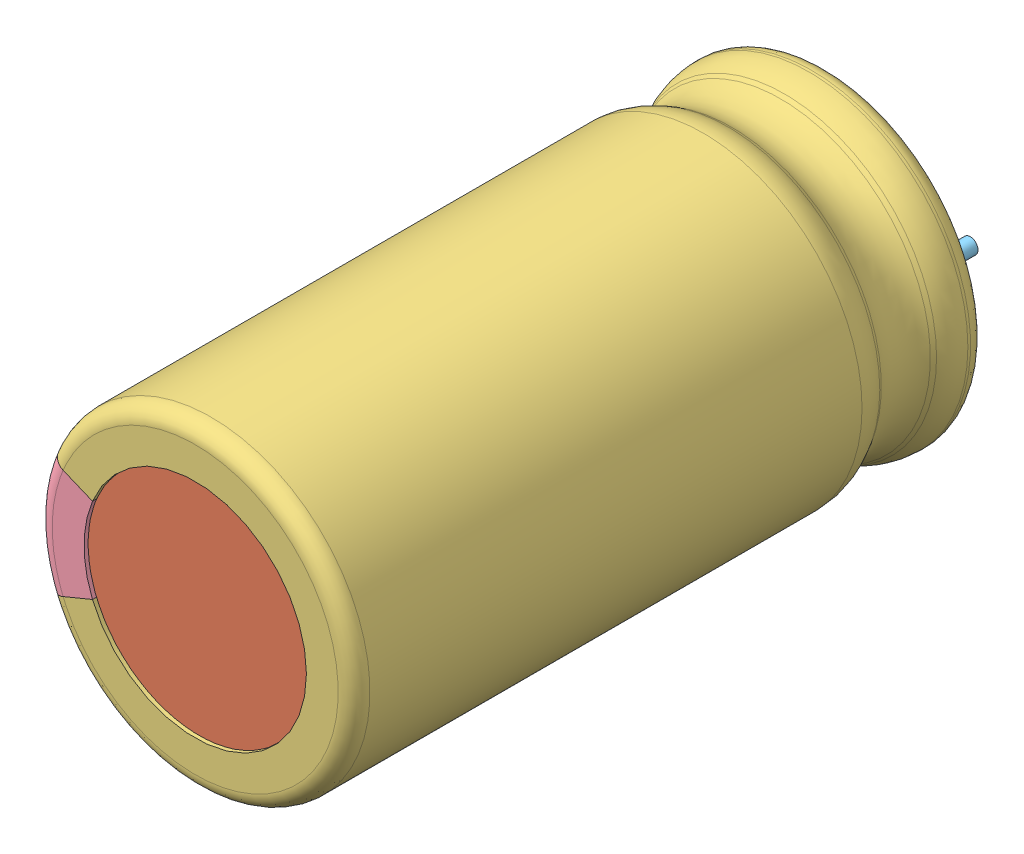
SolidWorks assembly User Library-CapAluRadial_D160H315, configuration Default. Lengths in mm.
Overall size (16.5 16.5 36.55).
6 component instances, 5 part files, 0 mates.
Components (placement in the parent):
- User Library-CapAluRadial_D160H315_rubber_pad-1: User Library-CapAluRadial_D160H315_rubber_pad [Default] at origin size (11.55 11.55 1)
- User Library-CapAluRadial_D160H315_can-1: User Library-CapAluRadial_D160H315_can [Default] at origin size (11.55 11.55 32.3)
- User Library-CapAluRadial_D160H315_shell_and_minus-1: User Library-CapAluRadial_D160H315_shell_and_minus [Default] at origin size (16.01 16.5 32.93)
- User Library-CapAluRadial_D160H315_shell_and_minus_2-1: User Library-CapAluRadial_D160H315_shell_and_minus_2 [Default] at origin size (2.91 6.76 32.93)
- User Library-CapAluRadial_D160H315_lead-1: User Library-CapAluRadial_D160H315_lead [Default] at (-3.75 0 0) size (0.8 0.8 3)
- User Library-CapAluRadial_D160H315_lead-2: User Library-CapAluRadial_D160H315_lead [Default] at (3.75 0 0) x (-1 0 0) z (0 0 1) size (0.8 0.8 3)
